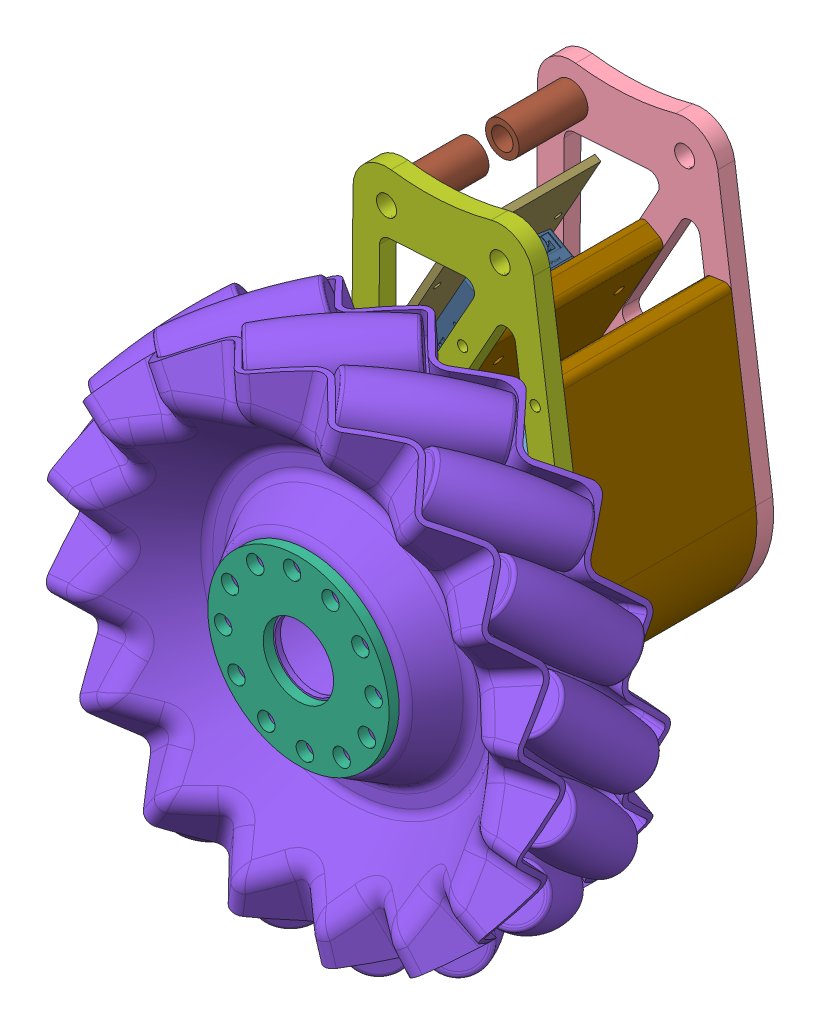
SolidWorks assembly 右旋轮组, configuration 默认. Lengths in mm.
Overall size (152.18 176.05 131.45).
14 component instances, 13 part files, 33 mates.
Components (placement in the parent):
- DP_RoboMaster GM3508无刷减速电机-1: DP_RoboMaster GM3508无刷减速电机 [默认] at origin size (42 44.98 98.4)
- 51100推力球轴承-1: 51100推力球轴承 [默认] at (34.8209 73.9788 28.9) size (24 24 10)
- DP_夹紧联轴器2-1: DP_夹紧联轴器2 [默认] at (34.8209 73.9788 33.9) x (-0.925598 -0.378508 0) z (0 0 1) size (47.97 54.2 10)
- 轮系支撑板 - 副-1: 轮系支撑板 - 副 [默认] at (34.8209 73.9788 -33.1) x (0.135002 0.990845 0) z (0.990845 -0.135002 0) size (128 5 76.21)
- DP_轮组端盖_1-1: DP_轮组端盖_1 [默认] at (34.8209 73.9788 43.9) size (19.5 19.5 10)
- DP_轮毂挡板_1-1: DP_轮毂挡板_1 [默认] at (34.8209 73.9788 72.5004) x (0.996363 0.085205 0) z (0 0 1) size (54 54 3)
- 轮系支撑板-1: 轮系支撑板 [默认] at (34.8209 73.9788 21.9) x (0.135002 0.990845 0) z (0.990845 -0.135002 0) size (128 5 76.21)
- DP_右旋_mecanum_wheel-1: DP_右旋_mecanum_wheel [默认] at (55.7485 66.293 189.0522) size (152.18 152.18 48.1)
- 轮组支撑打印件-1: 轮组支撑打印件 [默认] at (34.8209 73.9788 -3.1) x (0.135002 0.990845 0) z (0.990845 -0.135002 0) size (94.2 50 65.36)
- DP_C620无刷电机调速器-1: DP_C620无刷电机调速器 [默认] at (12.5309 109.8001 -3.1) x (-0.487386 -0.873186 0) z (0 0 1) size (103.05 11.5 26.13)
- 轮系套筒-1: 轮系套筒 [默认] at (12.4757 155.9891 -28.1) size (10 10 20.5)
- 轮系套筒-2: 轮系套筒 [默认] at (12.4757 155.9891 1.4) size (10 10 20.5)
- 垫柱-1: 垫柱 [默认] at (26.925 124.5088 -21.1) x (0.262485 0.47026 0.842589) z (-0.873186 0.487386 0) (suppressed, hidden)
- 亚克力保护-1: 亚克力保护 [默认] at (8.2628 117.747 -3.1) x (0.487386 0.873186 0) z (-0.873186 0.487386 0) size (70 42 2)
Mates (geometry in assembly coordinates):
- 重合1: coincident anti-aligned: plane of DP_RoboMaster GM3508无刷减速电机-1 through (30.5655 63.8352 23.9) normal (0 0 1); plane of 51100推力球轴承-1 through (34.8209 73.9788 23.9) normal (0 0 -1)
- 同心1: concentric anti-aligned: cylinder of DP_RoboMaster GM3508无刷减速电机-1 through (34.8209 73.9788 49.2) axis (0 0 1) radius 5; cylinder of 51100推力球轴承-1 through (34.8209 73.9788 33.9) axis (0 0 -1) radius 5
- 同心2: concentric anti-aligned: cylinder of DP_RoboMaster GM3508无刷减速电机-1 through (34.8209 73.9788 49.2) axis (0 0 1) radius 5; cylinder of DP_夹紧联轴器2-1 through (34.8209 73.9788 43.9) axis (0 0 -1) radius 5
- 重合2: coincident anti-aligned: plane of DP_RoboMaster GM3508无刷减速电机-1 through (36.0836 78.8167 29.2) normal (-0.378508 0.925598 0); plane of DP_夹紧联轴器2-1 through (36.0836 78.8167 43.9) normal (0.378508 -0.925598 0)
- 重合3: coincident anti-aligned: plane of 51100推力球轴承-1 through (34.8209 73.9788 33.9) normal (0 0 1); plane of DP_夹紧联轴器2-1 through (34.8209 73.9788 33.9) normal (0 0 -1)
- 重合4: coincident anti-aligned: plane of DP_夹紧联轴器2-1 through (34.8209 73.9788 43.9) normal (0 0 1); plane of DP_右旋_mecanum_wheel-1 through (34.8209 73.9788 43.9) normal (0 0 -1)
- 同心3: concentric aligned: cylinder of 51100推力球轴承-1 through (34.8209 73.9788 33.9) axis (0 0 -1) radius 12; cylinder of DP_右旋_mecanum_wheel-1 through (34.8209 73.9788 83.574) axis (0 0 -1) radius 10
- 同心4: concentric aligned: cylinder of DP_轮组端盖_1-1 through (34.8209 73.9788 53.9) axis (0 0 -1) radius 9.75; cylinder of DP_右旋_mecanum_wheel-1 through (34.8209 73.9788 83.574) axis (0 0 -1) radius 10
- 重合5: coincident anti-aligned: plane of DP_夹紧联轴器2-1 through (57.1527 70.8487 43.9) normal (0 0 1); plane of DP_轮组端盖_1-1 through (34.8209 73.9788 43.9) normal (0 0 -1)
- 重合6: coincident anti-aligned: plane of DP_轮毂挡板_1-1 through (34.8209 73.9788 72.5004) normal (0 0 -1); plane of DP_右旋_mecanum_wheel-1 through (34.8209 73.9788 72.5004) normal (0 0 1)
- 同心5: concentric aligned: cylinder of DP_轮毂挡板_1-1 through (34.8209 73.9788 75.5004) axis (0 0 -1) radius 10.5; cylinder of DP_右旋_mecanum_wheel-1 through (34.8209 73.9788 83.574) axis (0 0 -1) radius 10
- 同心6: concentric aligned: cylinder of DP_轮毂挡板_1-1 through (47.6902 55.5226 72.5004) axis (0 0 1) radius 2.6; cylinder of DP_右旋_mecanum_wheel-1 through (47.6902 55.5226 72.5004) axis (0 0 1) radius 2.6
- 重合7: coincident anti-aligned: plane of DP_RoboMaster GM3508无刷减速电机-1 through (29.7918 61.9909 21.9) normal (0 0 1); plane of 轮系支撑板-1 through (34.8209 73.9788 21.9) normal (0 0 -1)
- 距离1: distance = 50 mm anti-aligned: plane of 轮系支撑板 - 副-1 through (34.8209 73.9788 -28.1) normal (0 0 1); plane of 轮系支撑板-1 through (34.8209 73.9788 21.9) normal (0 0 -1)
- 同心7: concentric aligned: cylinder of 51100推力球轴承-1 through (34.8209 73.9788 33.9) axis (0 0 -1) radius 12; cylinder of 轮系支撑板-1 through (34.8209 73.9788 26.9) axis (0 0 -1) radius 13.1
- 重合8: coincident aligned: plane of 轮系支撑板 - 副-1 through (1.8219 74.2426 -28.1) normal (-0.999968 0.007994 0); plane of 轮系支撑板-1 through (1.8219 74.2426 26.9) normal (-0.999968 0.007994 0)
- 同心8: concentric anti-aligned: cylinder of 51100推力球轴承-1 through (34.8209 73.9788 33.9) axis (0 0 -1) radius 12; cylinder of 轮系支撑板 - 副-1 through (34.8209 73.9788 -38.1) axis (0 0 1) radius 24
- 同心9: concentric anti-aligned: cylinder of DP_RoboMaster GM3508无刷减速电机-1 through (18.6229 67.3549 21.9) axis (0 0 1) radius 1.65; cylinder of 轮系支撑板-1 through (18.6229 67.3549 26.9) axis (0 0 -1) radius 2.025
- 重合9: coincident anti-aligned: plane of 轮系支撑板 - 副-1 through (34.8209 73.9788 -28.1) normal (0 0 1); plane of 轮组支撑打印件-1 through (34.8209 73.9788 -28.1) normal (0 0 -1)
- 同心10: concentric aligned: cylinder of 轮系支撑板 - 副-1 through (31.1053 46.7086 -23.1) axis (0 0 -1) radius 1.525; cylinder of 轮组支撑打印件-1 through (31.1053 46.7086 21.9) axis (0 0 -1) radius 1.525
- 同心11: concentric aligned: cylinder of 轮系支撑板 - 副-1 through (62.0911 70.2632 -23.1) axis (0 0 -1) radius 1.525; cylinder of 轮组支撑打印件-1 through (62.0911 70.2632 21.9) axis (0 0 -1) radius 1.525
- 重合10: coincident anti-aligned: plane of 轮组支撑打印件-1 through (7.2961 89.3423 11.9) normal (-0.873186 0.487386 0); plane of DP_C620无刷电机调速器-1 through (18.0746 108.6526 -3.1) normal (0.873186 -0.487386 0)
- 宽度1: width aligned: plane of 轮系支撑板 - 副-1 through (34.8209 73.9788 -28.1) normal (0 0 1); plane of 轮系支撑板-1 through (34.8209 73.9788 21.9) normal (0 0 -1); plane of DP_C620无刷电机调速器-1 through (-1.9584 96.3573 9.8) normal (0 0 1); plane of DP_C620无刷电机调速器-1 through (-1.9584 96.3573 -16) normal (0 0 -1)
- 重合11: coincident: line of 轮组支撑打印件-1 through (6.0362 87.0849 -28.1) axis (0 0 1); plane of DP_C620无刷电机调速器-1 through (4.2898 88.0597 -3.1) normal (-0.487386 -0.873186 0)
- 同心12: concentric aligned: cylinder of 轮系套筒——12份-1 through (12.4757 155.9891 -7.6) axis (0 0 -1) radius 3.2; cylinder of 轮系套筒——12份-2 through (12.4757 155.9891 21.9) axis (0 0 -1) radius 3.2
- 同心13: concentric aligned: cylinder of 轮系支撑板-1 through (12.4757 155.9891 26.9) axis (0 0 -1) radius 3; cylinder of 轮系套筒——12份-2 through (12.4757 155.9891 21.9) axis (0 0 -1) radius 5
- 重合12: coincident anti-aligned: plane of 轮系支撑板-1 through (34.8209 73.9788 21.9) normal (0 0 -1); plane of 轮系套筒——12份-2 through (12.4757 155.9891 21.9) normal (0 0 1)
- 重合13: coincident anti-aligned: plane of 轮系支撑板 - 副-1 through (34.8209 73.9788 -28.1) normal (0 0 1); plane of 轮系套筒——12份-1 through (12.4757 155.9891 -28.1) normal (0 0 -1)
- 重合14: coincident anti-aligned: plane of 轮组支撑打印件-1 through (7.2961 89.3423 11.9) normal (-0.873186 0.487386 0); plane of 垫柱-1 through (26.925 124.5088 -21.1) normal (0.873186 -0.487386 0)
- 同心14: concentric anti-aligned: cylinder of 轮组支撑打印件-1 through (35.6569 119.6349 -21.1) axis (-0.873186 0.487386 0) radius 1.4; cylinder of 垫柱-1 through (15.5736 130.8448 -21.1) axis (0.873186 -0.487386 0) radius 3.25
- 重合15: coincident anti-aligned: plane of 垫柱-1 through (15.5736 130.8448 -21.1) normal (-0.873186 0.487386 0); plane of 亚克力保护-1 through (8.2628 117.747 -3.1) normal (0.873186 -0.487386 0)
- 同心15: concentric aligned: cylinder of 垫柱-1 through (15.5736 130.8448 -21.1) axis (0.873186 -0.487386 0) radius 3.25; cylinder of 亚克力保护-1 through (13.8272 131.8196 -21.1) axis (0.873186 -0.487386 0) radius 1.025
- 同心16: concentric anti-aligned: cylinder of 轮组支撑打印件-1 through (35.6569 119.6349 14.9) axis (-0.873186 0.487386 0) radius 1.4; cylinder of 亚克力保护-1 through (13.8272 131.8196 14.9) axis (0.873186 -0.487386 0) radius 1.025
